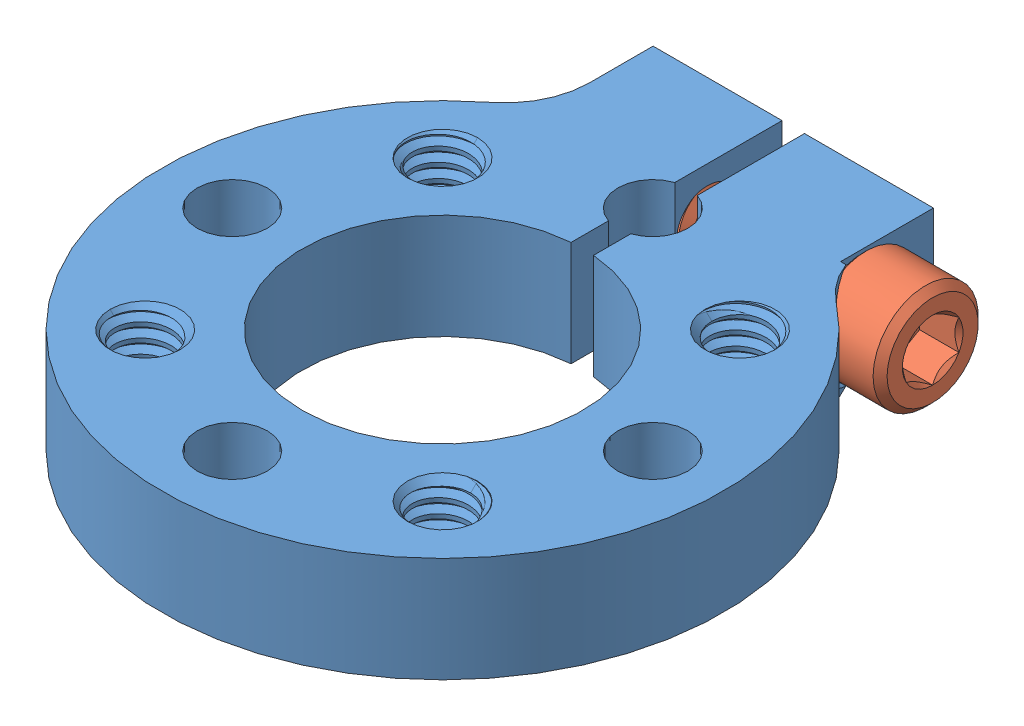
SolidWorks assembly Clamping hub 1inch, configuration Default. Lengths in mm.
Overall size (50.8 9.91 57.17).
2 component instances, 2 part files, 0 mates.
Components (placement in the parent):
- 545356-1: 545356 [Default] at (-68.793 17.8362 24.1343) size (50.8 9.91 57.17)
- 91251A542_91251A542-1: 91251A542_91251A542 [Default] at (-81.493 22.5987 -1.2123) x (0 0 1) z (-1 0 0) size (9.53 9.53 32.08)
